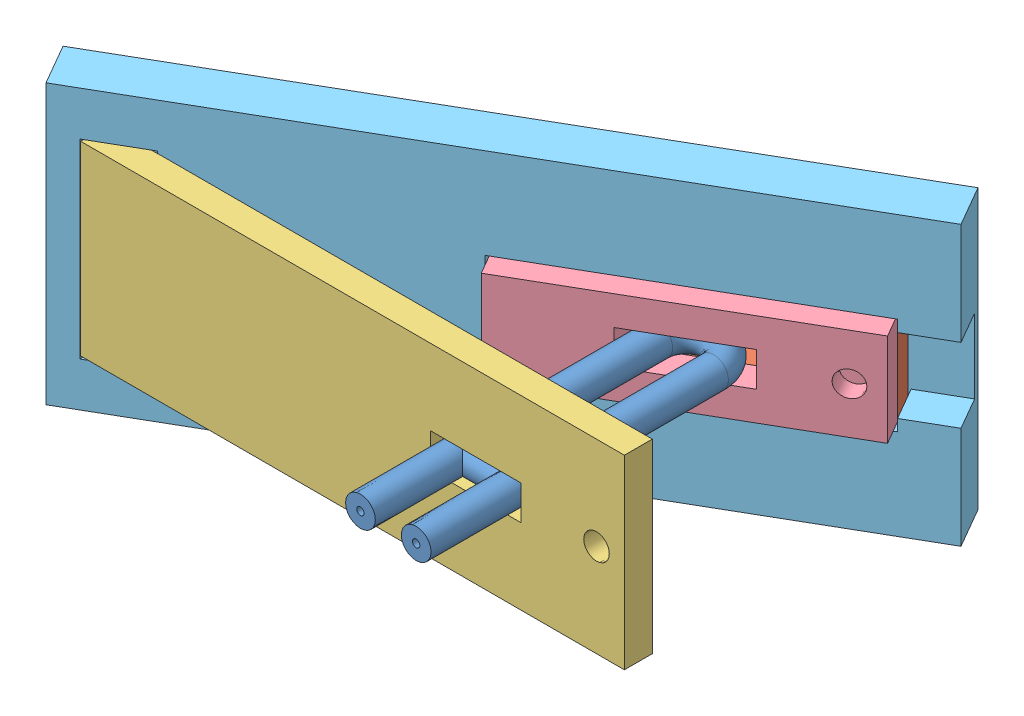
SolidWorks assembly utubeI_2 for water simulation, configuration 預設. Lengths in mm.
Overall size (64.91 30 48.35).
5 component instances, 5 part files, 6 mates.
Components (placement in the parent):
- u-tubeI_2 for water sumulation-2: u-tubeI_2 for water sumulation [預設] at (-10.7563 -0.0222 2.6) x (1 0 0) z (0 -1 0) size (9.2 36.6 3.2)
- heating block 1-1: heating block 1 [預設] at origin size (29.21 10 18.6)
- heatig block 2-1: heatig block 2 [預設] at origin size (58.5 20 3)
- heating block 1_2-2: heating block 1_2 [預設] at origin size (29.21 10 18.6)
- base-1: base [預設] at (-25.6153 -15 1.4335) x (-0.866025 0 0.5) z (-0.5 0 -0.866025) size (72.07 30 5)
Mates (geometry in assembly coordinates):
- 重合/共線/共點1: coincident anti-aligned: plane of heating block 1-1 through (-5.0331 -5 -8.7176) normal (0.5 0 0.866025); plane of heating block 1_2-2 through (-25.9175 -5 3.34) normal (-0.5 0 -0.866025)
- 重合/共線/共點2: coincident aligned: plane of heating block 1-1 through (-10.5063 -1.85 -2.4) normal (0 1 0); plane of heating block 1_2-2 through (0 -1.85 0) normal (0 1 0)
- 重合/共線/共點3: coincident aligned: plane of heating block 1-1 through (-20.8844 -5 12.0576) normal (-0.866025 0 0.5); plane of heating block 1_2-2 through (-24.4175 -5 5.9381) normal (-0.866025 0 0.5)
- 重合/共線/共點4: coincident anti-aligned: plane of heating block 1-1 through (-6.5331 -5 -11.3157) normal (-0.5 0 -0.866025); plane of base-1 through (-26.3653 -15 0.1344) normal (0.5 0 0.866025)
- 平行相距2: distance = 0.25 mm anti-aligned: plane of heating block 1_2-2 through (0 5 0) normal (0 1 0); plane of base-1 through (-27.634 5.25 0.8669) normal (0 -1 0)
- 平行相距1: distance = 0.25 mm anti-aligned: plane of heating block 1_2-2 through (1.7953 -5 -12.66) normal (0.866025 0 -0.5); plane of base-1 through (0.5118 -4 -15.3831) normal (-0.866025 0 0.5)
